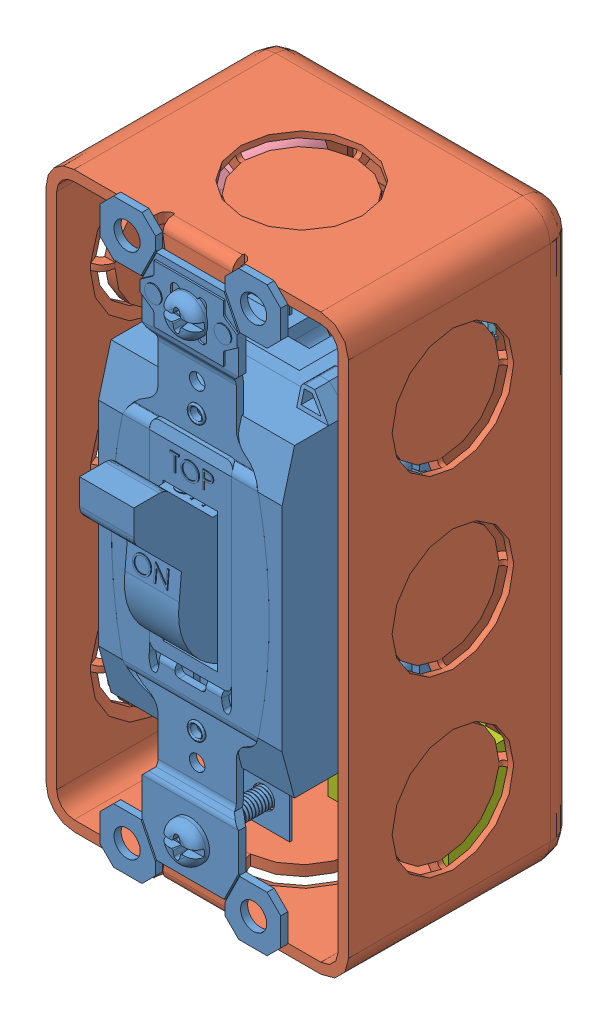
SolidWorks assembly fitcheck, configuration Default. Lengths in mm.
Overall size (55.25 106.17 85.65).
14 component instances, 13 part files, 8 mates.
Components (placement in the parent):
- 7030K321_Toggle Light Switch-1: 7030K321_Toggle Light Switch [7030K321] at (0 0 -12.3317) size (39.46 106.17 45.8)
- 7159K91_Straight-Blade Receptacle-1: 7159K91_Straight-Blade Receptacle [7159K91] at (0 0 6.35) size (40.13 106.68 27.18) (hidden)
- Single Gang Box 1-1: Single Gang Box 1 [100260-1] x (1 0 0) z (0 0 -1) size (55.25 104.77 85.65)
- pcb-1: pcb [Default] at (-2.0761 -2.5895 0) size (45 97.6 20.3)
  - fuse-1: fuse [Default] at (53.9119 94.1783 -36.005) x (0 -1 0) z (0 0 1) size (18.26 5.49 12.67)
  - C13_part004_cfcfa7a77c9f^Bot_e2fb_Step_Models_e2fb_fullboard(2)_fullboard-1: C13_part004_cfcfa7a77c9f^Bot_e2fb_Step_Models_e2fb_fullboard(2)_fullboard [Default] at (-17.4296 44.058 -36.005) size (10.05 10.01 20.14)
  - EEE-HC1H220XP_EEE-HC1H220XP004^C12_EEE-HC1H220XP_ed344a759db5_Bot_e2fb_Step_Models_e2fb_fullboard(2)_fullboard-1: EEE-HC1H220XP_EEE-HC1H220XP004^C12_EEE-HC1H220XP_ed344a759db5_Bot_e2fb_Step_Models_e2fb_fullboard(2)_fullboard [Default] at (17.305 31.0597 -36.005) x (1 0 0) z (0 -1 0) size (7.3 7.7 6.6)
  - J1_USB4110-GF-A_revB_7df47bc8146b^Bot_e2fb_Step_Models_e2fb_fullboard(2)_fullboard-1: J1_USB4110-GF-A_revB_7df47bc8146b^Bot_e2fb_Step_Models_e2fb_fullboard(2)_fullboard [Default] at (-15.2749 -5.8476 -36.005) x (0 -1 0) z (-1 0 0) size (11.3 3.89 7.7)
  - J2_C-2-1437667-9_6eec27b8f94b^Bot_e2fb_Step_Models_e2fb_fullboard(2)_fullboard-1: J2_C-2-1437667-9_6eec27b8f94b^Bot_e2fb_Step_Models_e2fb_fullboard(2)_fullboard [Default] at (-101.8511 -38.0102 30.9942)
  - K1_G5CA_1A_fa65c8f1b37e(2)^Top_e2fb_Step_Models_e2fb_fullboard(2)_fullboard-1: K1_G5CA_1A_fa65c8f1b37e(2)^Top_e2fb_Step_Models_e2fb_fullboard(2)_fullboard [Default] at (20.7836 -32.7933 -36.005) x (-1 0 0) z (0 1 0) size (22 14.5 16)
  - L2_part008_54176d0c7ac0^Bot_e2fb_Step_Models_e2fb_fullboard(2)_fullboard-1: L2_part008_54176d0c7ac0^Bot_e2fb_Step_Models_e2fb_fullboard(2)_fullboard [Default] at (-3.3112 38.4242 -36.005) size (9.24 9.22 17.53)
  - PS1_LS01-K3B05SS021_a3dcc8fdcf56^Top_e2fb_Step_Models_e2fb_fullboard(2)_fullboard-1: PS1_LS01-K3B05SS021_a3dcc8fdcf56^Top_e2fb_Step_Models_e2fb_fullboard(2)_fullboard [Default] at (14.2899 39.6149 -35.505) x (-0.999962 0.008727 0) z (0.008727 0.999962 0) size (16.13 18.17 9.5)
  - U2_ESP32-WROOM-32_49e9e5f5a815(2)^Top_e2fb_Step_Models_e2fb_fullboard(2)_fullboard-1: U2_ESP32-WROOM-32_49e9e5f5a815(2)^Top_e2fb_Step_Models_e2fb_fullboard(2)_fullboard [Default] at (-10.8552 -22.4956 -36.005) x (-1 0 0) z (0 0 1) size (18 25.5 3.1)
  - NewPCBOutline-1: NewPCBOutline [Default] at (0.9451 6.2275 -37.005) size (45 97.6 1)
Mates (geometry in assembly coordinates):
- Concentric1: concentric anti-aligned: line of 7159K91_Straight-Blade Receptacle-1 through (0 41.6687 16.7921) axis (0 0 -1); cylinder of Single Gang Box 1-1 through (0 41.6687 -1.905) axis (0 0 1) radius 1.5875
- Coincident5: coincident: point of 7159K91_Straight-Blade Receptacle-1; plane of Single Gang Box 1-1 through (0 0 0) normal (1 0 0)
- Coincident6: coincident anti-aligned: plane of 7159K91_Straight-Blade Receptacle-1 through (9.525 53.34 0) normal (0 0 -1); plane of Single Gang Box 1-1 through (6.35 0 0) normal (0 0 1)
- Concentric2: concentric anti-aligned: line of 7030K321_Toggle Light Switch-1 through (0 41.6687 11.639) axis (0 0 -1); cylinder of Single Gang Box 1-1 through (0 41.6687 -1.905) axis (0 0 1) radius 1.5875
- Coincident7: coincident anti-aligned: plane of 7030K321_Toggle Light Switch-1 through (16.51 53.086 0) normal (0 0 -1); plane of Single Gang Box 1-1 through (6.35 0 0) normal (0 0 1)
- Parallel1: parallel aligned: plane of 7030K321_Toggle Light Switch-1 through (0 0 -12.3317) normal (1 0 0); plane of Single Gang Box 1-1 through (0 0 0) normal (1 0 0)
- Parallel9: parallel anti-aligned: plane of Single Gang Box 1-1 through (22.5425 -47.3075 -40.005) normal (0 0 1); plane of Assem52^fitcheck-1/NewPCBOutline-1 through (-1.131 3.6381 -37.005) normal (0 0 -1)
- Distance3: distance = 3 mm anti-aligned: plane of Assem52^fitcheck-1/NewPCBOutline-1 through (-1.131 3.6381 -37.005) normal (0 0 -1); plane of Single Gang Box 1-1 through (22.5425 -47.3075 -40.005) normal (0 0 1)
